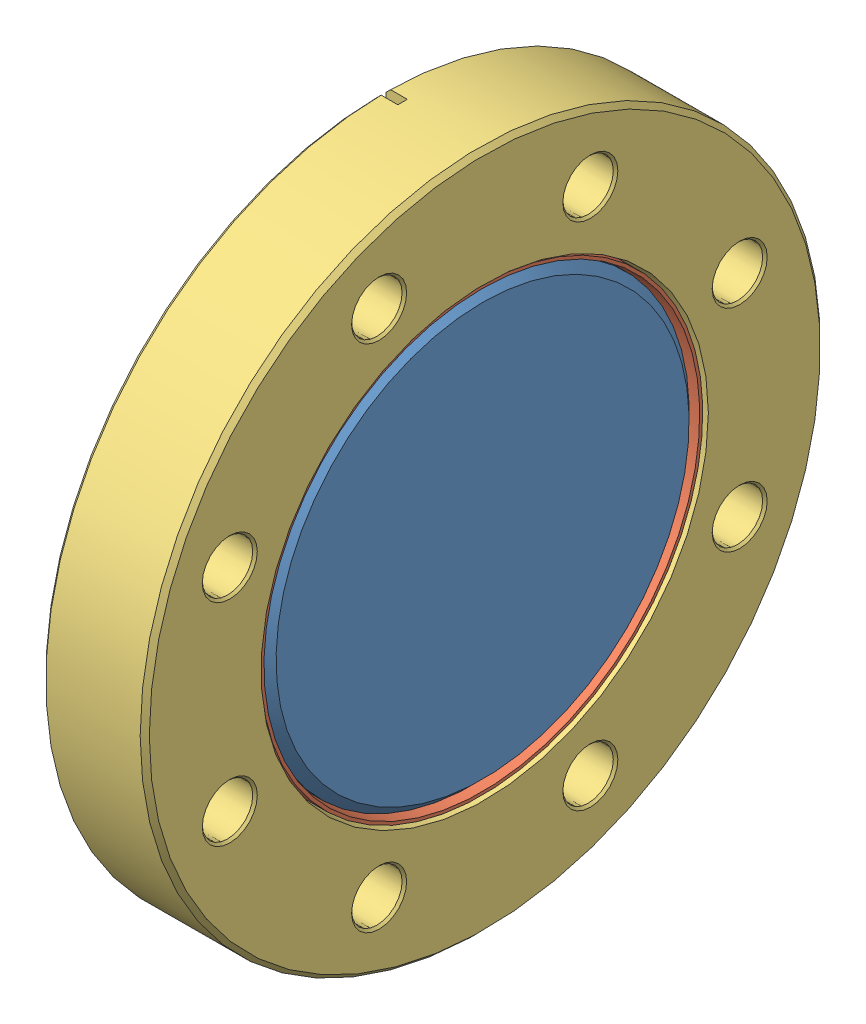
SolidWorks assembly Viewport 4.5_9722007, configuration Default. Lengths in mm.
Overall size (17.27 113.54 113.54).
4 component instances, 3 part files, 0 mates.
Components (placement in the parent):
- 1004602A-1: 1004602A [Default] at (1.2954 0 0) x (0 1 0) z (-1 0 0) size (73.79 73.79 15.62)
  - 1002203A-1: 1002203A [Default] at (0 0 -9.271) x (-1 0 0) z (0 0 -1) size (72.01 72.01 6.35)
  - Viewport 4.5 P1_0194302B-1: Viewport 4.5 P1_0194302B [Default] at origin size (73.79 73.79 15.49)
- Viewport 4.5 P2_0194603B-1: Viewport 4.5 P2_0194603B [Default] at origin size (17.27 113.54 113.54)
